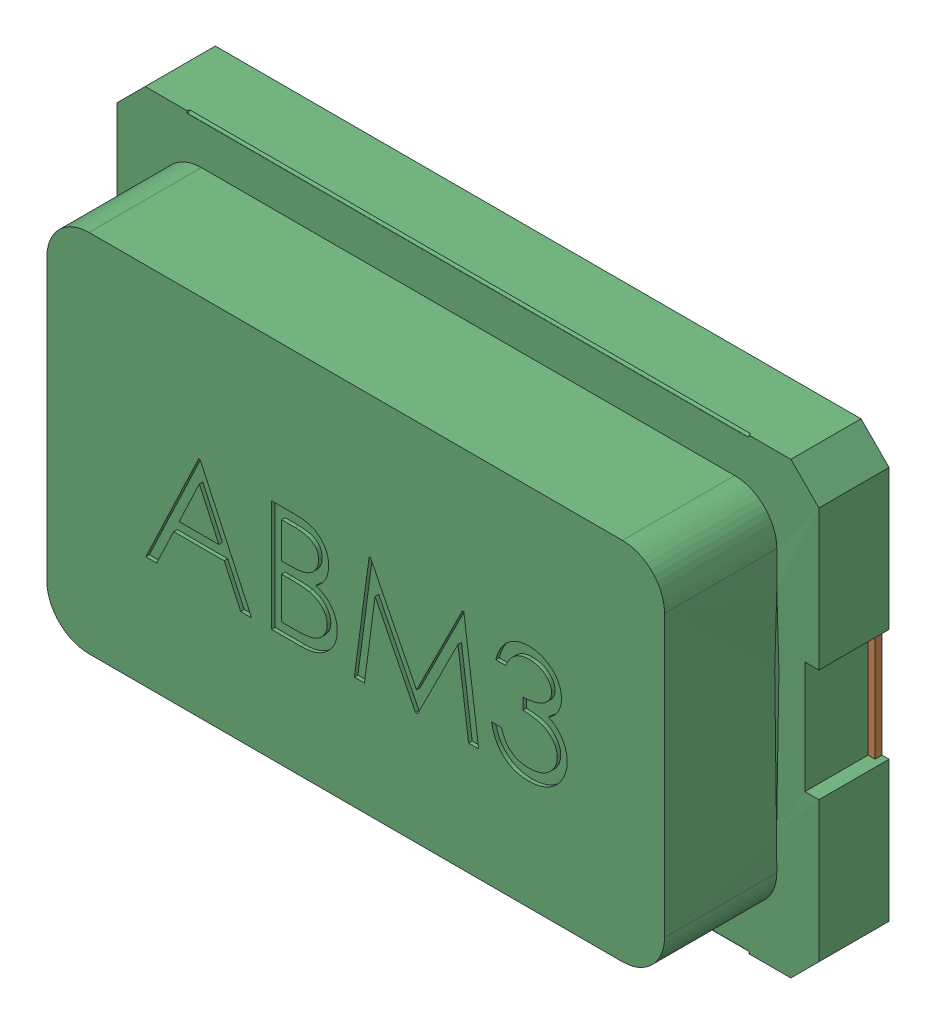
SolidWorks assembly U2, configuration Predeterminado. Lengths in mm.
Overall size (5 3.22 1.3).
5 component instances, 3 part files, 0 mates.
Components (placement in the parent):
- Open CASCADE STEP translator 6.8 1.4.1-1: Open CASCADE STEP translator 6.8 1.4.1 [Predeterminado] at origin size (5 3.22 1.3)
  - Body_1_2-1: Body_1_2 [Predeterminado] at (0 0 0.25) x (1 0 0) z (0 -1 0) size (5 1.3 3.22)
    - =_[0_1_1_3]-1: =_[0_1_1_3] [Predeterminado] at origin size (1.25 0.05 2)
    - =_[0_1_1_4]-1: =_[0_1_1_4] [Predeterminado] at origin size (1.25 0.05 2)
    - =_[0_1_1_5]-1: =_[0_1_1_5] [Predeterminado] at origin size (5 1.3 3.22)
